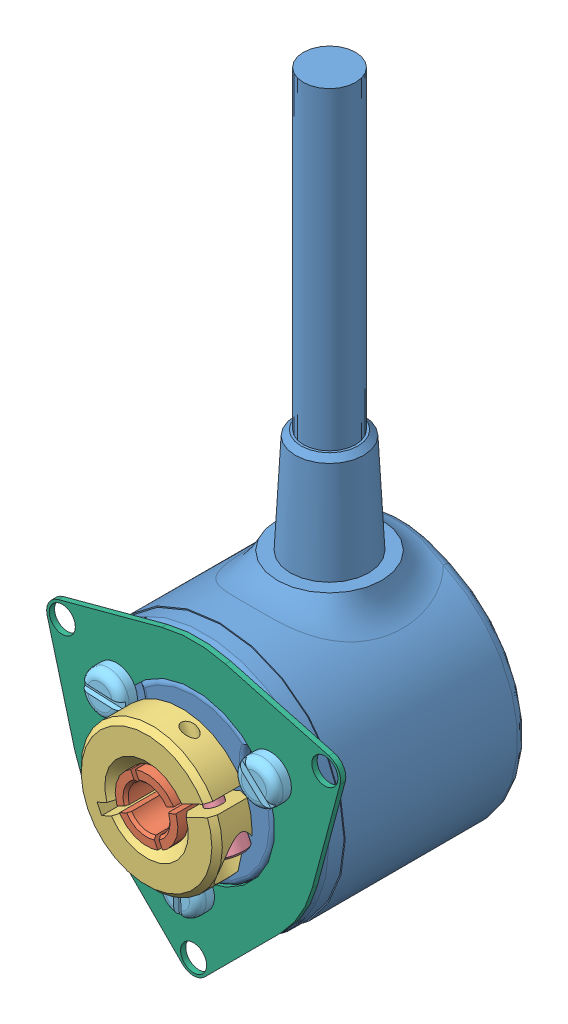
SolidWorks assembly Codeur_2MRH, configuration Default. Lengths in mm.
Overall size (38.09 70.8 24.5).
8 component instances, 6 part files, 16 mates.
Components (placement in the parent):
- corps_codeur_2MRH-1: corps_codeur_2MRH [Default] at (3.2886 -2.5929 -14.3048) size (24 64.75 20.04)
- mandrin_codeur_2MRH-1: mandrin_codeur_2MRH [Default] at (3.2886 -2.5929 -3.8048) x (-0.434638 0.900605 0) z (0 0 1) size (6 6 14)
- bague_codeur_2MRH-1: bague_codeur_2MRH [Default] at (3.2886 -2.5929 5.6952) x (0.434638 -0.900605 0) z (0 0 1) size (13.5 13.48 4.5)
- Socket Head Cap Screw_AM-1: Socket Head Cap Screw_AM [B18.3.1M - 1.6 x 0.35 x 5 Hex SHCS -- 5NHX] at (9.1066 -4.3376 7.9452) x (-0.434638 0.900605 0) z (0 0 1) size (6.6 3 3)
- Pan Slot Head_AM-4: Pan Slot Head_AM [B18.6.7M - M2 x 0.4 x 4 Slotted PHMS --4N] at (10.6498 1.6571 7.2952) x (0 0 -1) z (0.728333 -0.685223 0) size (5.65 4 4)
- Pan Slot Head_AM-5: Pan Slot Head_AM [B18.6.7M - M2 x 0.4 x 4 Slotted PHMS --4N] at (-4.0726 1.6571 7.2952) x (0 0 -1) z (0.998972 -0.045336 0) size (5.65 4 4)
- Pan Slot Head_AM-6: Pan Slot Head_AM [B18.6.7M - M2 x 0.4 x 4 Slotted PHMS --4N] at (3.2886 -11.0929 7.2952) x (0 0 -1) z (-0.043781 0.999041 0) size (5.65 4 4)
- Bride_membrane-1: Bride_membrane [Default] at (3.2886 -2.5929 5.6952) x (0.5 0.866025 0) z (-0.866025 0.5 0) size (28.11 0.5 27.75)
Mates (geometry in assembly coordinates):
- Coaxiale2: concentric anti-aligned: cylinder of corps_codeur_2MRH-1; cylinder of mandrin_codeur_2MRH-1
- Coïncidente1: coincident anti-aligned: plane of corps_codeur_2MRH-1 through (3.2886 -2.5929 -3.8048) normal (0 0 1); plane of mandrin_codeur_2MRH-1 through (3.2886 -2.5929 -3.8048) normal (0 0 -1)
- Coïncidente2: coincident anti-aligned: plane of corps_codeur_2MRH-1 through (3.2886 -2.5929 5.6952) normal (0 0 1); plane of bague_codeur_2MRH-1 through (3.2886 -2.5929 5.6952) normal (0 0 -1)
- Coaxiale3: concentric aligned: cylinder of mandrin_codeur_2MRH-1; cylinder of bague_codeur_2MRH-1
- Parallèle1: parallel aligned: plane of mandrin_codeur_2MRH-1 through (3.4051 -2.2591 0.1952) normal (0.434638 -0.900605 0); plane of bague_codeur_2MRH-1 through (9.1337 0.7831 5.6942) normal (0.434638 -0.900605 0)
- Coaxiale41: concentric anti-aligned: cylinder of bague_codeur_2MRH-1; cylinder of Socket Head Cap Screw_AM-1
- Coïncidente41: coincident anti-aligned: plane of bague_codeur_2MRH-1 through (8.4112 -2.8966 7.9452) normal (0.434638 -0.900605 0); plane of Socket Head Cap Screw_AM-1 through (7.0603 -3.5486 7.9452) normal (-0.434638 0.900605 0)
- Coaxiale81: concentric aligned: cylinder of corps_codeur_2MRH-1; cylinder of Pan Slot Head_AM-4
- Coaxiale91: concentric aligned: cylinder of corps_codeur_2MRH-1; cylinder of Pan Slot Head_AM-5
- Coaxiale101: concentric aligned: cylinder of corps_codeur_2MRH-1; cylinder of Pan Slot Head_AM-6
- Coïncidente102: coincident anti-aligned: plane of corps_codeur_2MRH-1 through (3.2886 -2.5929 5.1952) normal (0 0 1); plane of Bride_membrane-1 through (3.2886 -2.5929 5.1952) normal (0 0 -1)
- Coïncidente103: coincident aligned: circle of corps_codeur_2MRH-1; cylinder of Bride_membrane-1
- Coaxiale102: concentric aligned: cylinder of corps_codeur_2MRH-1; cylinder of Bride_membrane-1
- Coïncidente104: coincident anti-aligned: plane of Pan Slot Head_AM-5 through (-4.0273 2.6561 5.6952) normal (0 0 -1); plane of Bride_membrane-1 through (3.2886 -2.5929 5.6952) normal (0 0 1)
- Coïncidente105: coincident anti-aligned: plane of Pan Slot Head_AM-4 through (11.335 2.3854 5.6952) normal (0 0 -1); plane of Bride_membrane-1 through (3.2886 -2.5929 5.6952) normal (0 0 1)
- Coïncidente106: coincident anti-aligned: plane of Pan Slot Head_AM-6 through (2.2896 -11.1367 5.6952) normal (0 0 -1); plane of Bride_membrane-1 through (3.2886 -2.5929 5.6952) normal (0 0 1)
